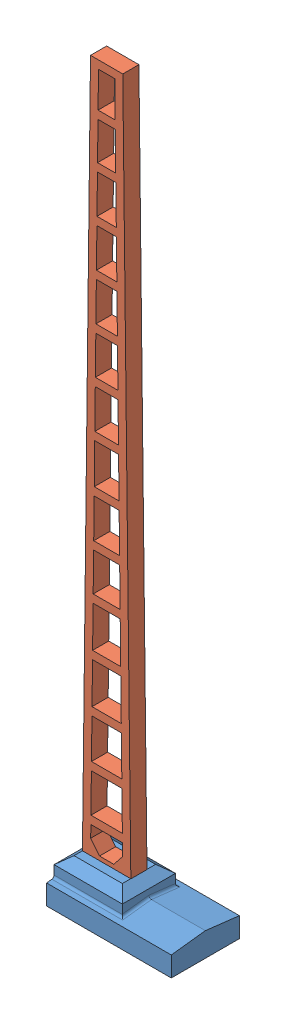
SolidWorks assembly Ensamblaje2, configuration Default. Lengths in mm.
Overall size (38.64 227.11 21.11).
2 component instances, 2 part files, 0 mates.
Components (placement in the parent):
- base superior-1: base superior [Default] at (-75.4227 16.4462 52.29) size (38.64 12.36 21.11)
- catenaria mastil 01-1: catenaria mastil 01 [Default] at (-68.45 6.45 47.3426) x (0 1 0) z (1 0 0) size (219 5 15)
